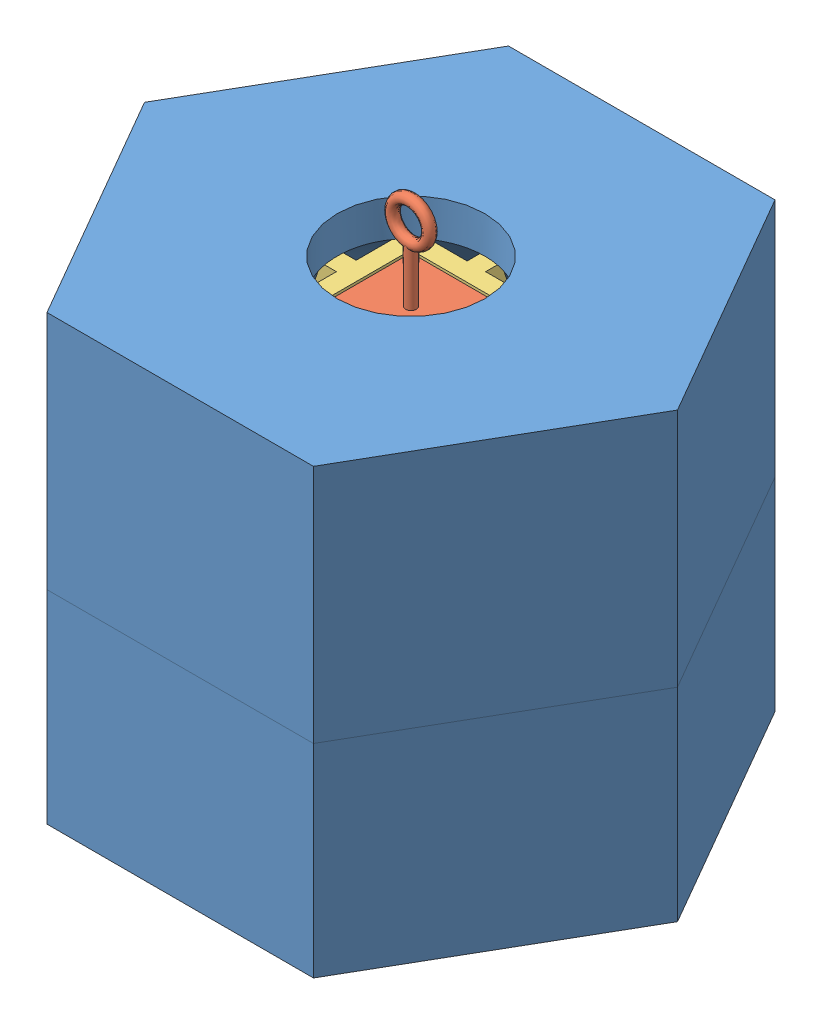
SolidWorks assembly mold assembly, configuration Default. Lengths in mm.
Overall size (144.34 134.57 125).
4 component instances, 3 part files, 15 mates.
Components (placement in the parent):
- mold_master-1: mold_master [Default] at (0 -55 0) size (144.34 120 125)
- skeleton_assy-1: skeleton_assy [Default] at (-0.2 41.0652 -0.2) size (75 120.8 75)
  - mount-1: mount [Default] at origin size (25 38.5 25)
  - Skeleton_9-1: Skeleton_9 [Default] at (0.2 -37.3 0.2) x (0 0 -1) z (-1 0 0) size (75 95 75)
Mates (geometry in assembly coordinates):
- Coincident2: coincident aligned: plane of mold_master-1 through (0 0 0) normal (0 1 0)
- Coincident3: coincident aligned: plane of mold_master-1 through (0 -55 0) normal (1 0 0)
- Coincident4: coincident aligned: plane of mold_master-1 through (0 -55 0) normal (0 0 1)
- Coincident5: coincident aligned: plane of mold_master-1 through (0 -55 0) normal (0 0 1); plane of Skeleton_5-1 through (0 6.0598 0) normal (0 0 1)
- Coincident6: coincident aligned: plane of mold_master-1 through (0 -55 0) normal (1 0 0); plane of Skeleton_5-1 through (0 6.0598 0) normal (1 0 0)
- Coincident7: coincident anti-aligned: plane of mold_master-1 through (0 3.7652 0) normal (0 -1 0); plane of Skeleton_7-1 through (0 3.7652 0) normal (0 1 0)
- Coincident8: coincident aligned: plane of mold_master-1 through (0 -55 0) normal (0 0 1); plane of Skeleton_7-1 through (0 3.7652 0) normal (0 0 1)
- Coincident9: coincident aligned: plane of mold_master-1 through (0 -55 0) normal (1 0 0); plane of Skeleton_7-1 through (0 3.7652 0) normal (1 0 0)
- Coincident10: coincident anti-aligned: plane of Skeleton_8-1 through (0 3.7652 0) normal (0 0 -1)
- Coincident11: coincident aligned: plane of mold_master-1 through (0 3.7652 0) normal (0 -1 0); plane of Skeleton_8-1 through (0 3.7652 0) normal (0 -1 0)
- Coincident12: coincident aligned: plane of mold_master-1 through (0 -55 0) normal (1 0 0); plane of Skeleton_8-1 through (0 3.7652 0) normal (1 0 0)
- Coincident13: coincident anti-aligned: plane of skeleton_assy-1/Skeleton_8-1 through (0 3.7652 0) normal (-1 0 0)
- Coincident14: coincident aligned: plane of mold_master-1 through (0 3.7652 0) normal (0 -1 0); plane of skeleton_assy-1/Skeleton_8-1 through (0 3.7652 0) normal (0 -1 0)
- Coincident15: coincident anti-aligned: plane of skeleton_assy-1/Skeleton_8-1 through (0 3.7652 0) normal (-1 0 0)
- Coincident16: coincident anti-aligned: plane of mold_master-1 through (0 -55 0) normal (0 0 1); plane of skeleton_assy-1/Skeleton_8-1 through (0 3.7652 0) normal (0 0 -1)
